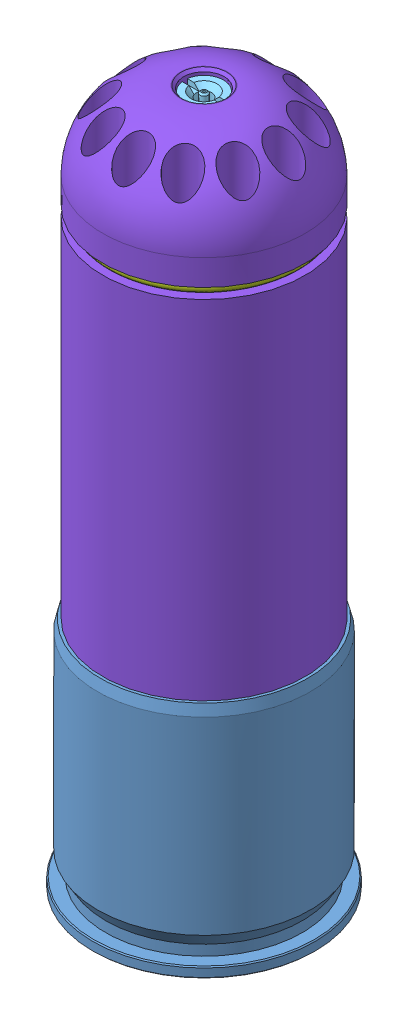
SolidWorks assembly 40mm-Groß, configuration Standard. Lengths in mm.
Overall size (42.9 134 42.9).
11 component instances, 8 part files, 20 mates.
Components (placement in the parent):
- Boden-G-1: Boden-G [Standard] at (-10.8436 -22.8172 45) size (42.9 45 42.9)
- Drücker-G-1: Drücker-G [Standard] at (-10.8436 -22.8172 45) size (14 23 14)
- value-1: value [Standard] at (-10.8436 -4.0172 45) size (20 21.5 20)
- Lock-Kugel-1: Lock-Kugel [Standard] at (-10.8436 -3.0172 55) size (4 4 4)
- Lock-Kugel-2: Lock-Kugel [Standard] at (-0.8436 -3.0172 45) size (4 4 4)
- Lock-Kugel-3: Lock-Kugel [Standard] at (-20.8436 -3.0172 45) size (4 4 4)
- Lock-Kugel-4: Lock-Kugel [Standard] at (-10.8436 -3.0172 35) size (4 4 4)
- Einfüllventil-1: Einfüllventil [Standard] at (-10.8436 97.6828 45) size (7.5 12.5 7.5)
- value-gegen-1: value-gegen [Standard] at (-10.8436 11.4828 45) x (1 0 -0.000025) z (0.000025 0 1) size (17.5 18.5 17.5)
- O-Ring oben-1: O-Ring oben [Standard] at (-10.8436 90.1828 45) x (0.998065 0 -0.062178) z (0.062178 0 0.998065) size (37 2 37)
- Vorn-G-1: Vorn-G [Standard] at (-10.8436 5.6828 45) x (0.998065 0 -0.062178) z (0.062178 0 0.998065) size (39 105.5 39)
Mates (geometry in assembly coordinates):
- Konzentrisch1: concentric anti-aligned: cylinder of Boden-G-1 through (-10.8436 -21.8172 45) axis (0 1 0) radius 7; cylinder of Drücker-G-1 through (-10.8436 -12.8172 45) axis (0 -1 0) radius 7
- Deckungsgleich1: coincident aligned: plane of Boden-G-1 through (-10.8436 -22.8172 45) normal (0 -1 0); plane of Drücker-G-1 through (-10.8436 -22.8172 45) normal (0 -1 0)
- Konzentrisch2: concentric: cylinder of value-1 through (-10.8436 70.3334 35) axis (0 0 1) radius 2; sphere of Lock-Kugel-1
- Tangential2: tangent: curve of value-1; sphere of Lock-Kugel-1
- Konzentrisch3: concentric: cylinder of value-1 through (-20.8436 70.3334 45) axis (1 0 0) radius 2; sphere of Lock-Kugel-2
- Tangential4: tangent: curve of value-1; sphere of Lock-Kugel-2
- Konzentrisch4: concentric: cylinder of value-1 through (-10.8436 70.3334 35) axis (0 0 1) radius 2; sphere of Lock-Kugel-4
- Tangential6: tangent: curve of value-1; sphere of Lock-Kugel-4
- Konzentrisch5: concentric: cylinder of value-1 through (-20.8436 70.3334 45) axis (1 0 0) radius 2; sphere of Lock-Kugel-3
- Tangential8: tangent: curve of value-1; sphere of Lock-Kugel-3
- Deckungsgleich2: coincident aligned: circle of Boden-G-1; cylinder of value-1 through (-10.8436 76.3334 45) axis (0 -1 0) radius 10
- Deckungsgleich5: coincident anti-aligned: plane of value-1 through (-10.8436 82.8334 45) normal (0 1 0); plane of value-gegen-1 through (-10.8436 82.8334 45) normal (0 -1 0)
- Konzentrisch8: concentric aligned: cylinder of value-1 through (-10.8436 88.8334 45) axis (0 -1 0) radius 4.95; cylinder of value-gegen-1 through (-10.8436 90.6334 45) axis (0 -1 0) radius 5
- Konzentrisch9: concentric anti-aligned: cylinder of Einfüllventil-1 through (-10.8436 179.5334 45) axis (0 -1 0) radius 2; cylinder of Vorn-G-1 through (-10.8436 77.0334 45) axis (0 1 0) radius 2
- Deckungsgleich6: coincident anti-aligned: plane of Einfüllventil-1 through (-10.8436 179.5334 45) normal (0 -1 0); plane of Vorn-G-1 through (-10.8436 179.5334 45) normal (0 1 0)
- Tangential9: tangent: torus of O-Ring oben-1; cylinder of Vorn-G-1 through (-10.8436 182.5334 45) axis (0 1 0) radius 16.5
- Tangential10: tangent: torus of O-Ring oben-1; plane of Vorn-G-1 through (-32.7794 160.5334 46.3666) normal (0 1 0)
- Konzentrisch10: concentric aligned: cylinder of value-gegen-1 through (-10.8436 101.3334 45) axis (0 -1 0) radius 7.5; cylinder of Vorn-G-1 through (-10.8436 170.0334 45) axis (0 -1 0) radius 7.5
- Deckungsgleich7: coincident anti-aligned: plane of value-gegen-1 through (-10.8436 84.8334 45) normal (0 1 0); plane of Vorn-G-1 through (-10.8436 84.8334 45) normal (0 -1 0)
- Deckungsgleich8: coincident anti-aligned: plane of Boden-G-1 through (-10.8436 22.1828 45) normal (0 1 0); plane of Vorn-G-1 through (-10.8436 22.1828 45) normal (0 -1 0)
